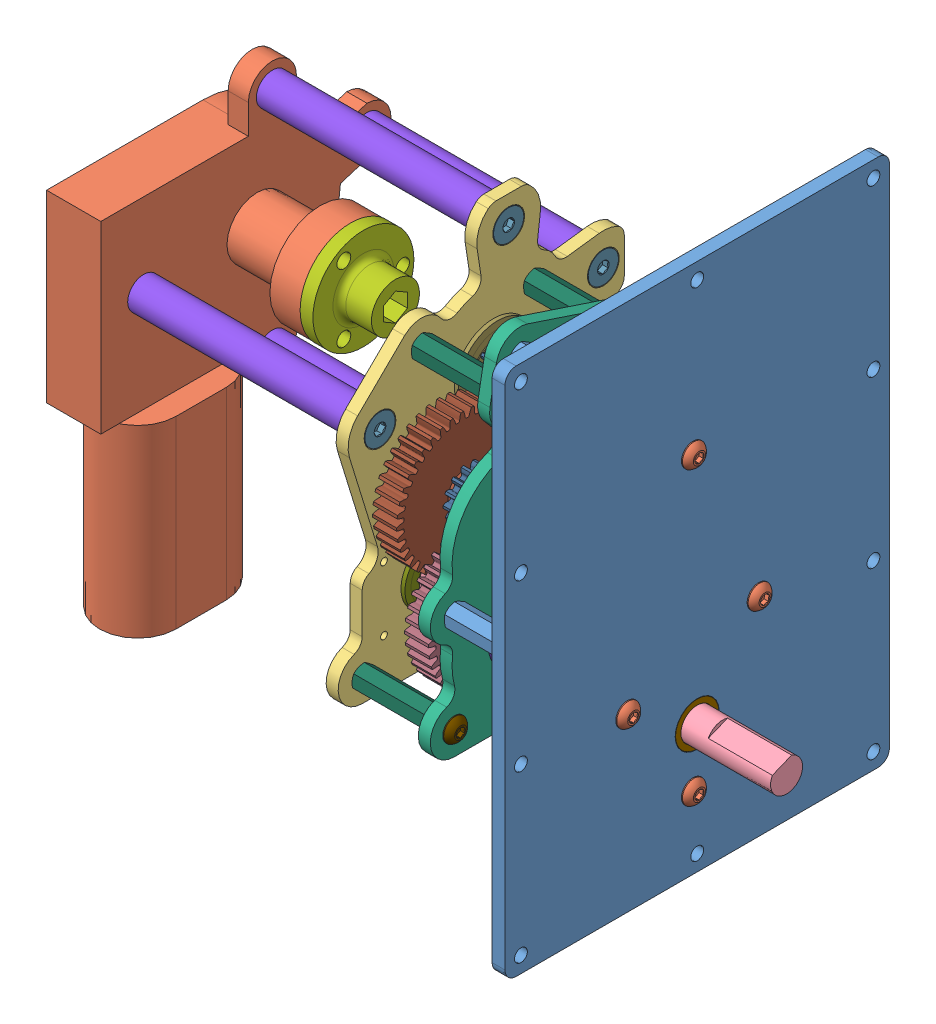
SolidWorks assembly Movable_Ballst_Motor_Assembly, configuration FEA. Lengths in mm.
Overall size (255.69 212.87 153.62).
50 component instances, 20 part files, 111 mates.
Components (placement in the parent):
- Ballast_Deck_Mount-1: Ballast_Deck_Mount [Default] at (82.4237 46.6127 298.7435) size (5.08 209.55 152.4)
- Ballast_Motor_Mock-1: Ballast_Motor_Mock [Default] at (-132.7513 189.2963 198.1531) x (1 0 0) z (0 -1 0) size (58.5 115.03 167.12)
- Ballast_Motor_Mount-1: Ballast_Motor_Mount [Default] at (-22.3513 65.6627 146.3435) x (1 0 0) z (0 -1 0) size (4.76 113.4 146.05)
- Movable_Ballast_Shaft-1: Movable_Ballast_Shaft [Default] at (122.9367 97.4127 222.5435) x (-1 0 0) z (0 -0.925827 -0.377948) size (146.05 14.66 12.7)
- Ballast_Gear_Shaft-1: Ballast_Gear_Shaft [Default] at (-23.9388 131.9059 222.5435) x (1 0 0) z (0 -0.052397 -0.998626) size (44.45 11 9.53)
- Ballast_GearBox_Mount-2: Ballast_GearBox_Mount [Default] at (14.1612 65.6627 165.3935) x (1 0 0) z (0 -1 0) size (4.76 87 134.58)
- Ballast_Motor_Hub-1: Ballast_Motor_Hub [Default] at (-74.2513 156.2963 198.1531) x (0 -1 0) z (1 0 0) size (40 40 17.78)
- CustomeStandoff_3_5in-1: CustomeStandoff_3_5in [92510A455] at (-66.8013 111.6963 192.1531) x (0 0 -1) z (1 0 0) size (12.7 12.7 88.9)
- CustomeStandoff_3_5in-2: CustomeStandoff_3_5in [92510A455] at (-66.8013 200.8963 192.1531) x (0 0 -1) z (1 0 0) size (12.7 12.7 88.9)
- CustomeStandoff_3_5in-3: CustomeStandoff_3_5in [92510A455] at (-66.8013 167.5963 154.6531) x (0 0.458553 0.888667) z (1 0 0) size (12.7 12.7 88.9)
- CustomeStandoff_3_5in-4: CustomeStandoff_3_5in [92510A455] at (-66.8013 156.2963 243.1531) x (0 0 -1) z (1 0 0) size (12.7 12.7 88.9)
- 13125K810_CHEMICAL-RESISTANT SHAFT SEAL-1: 13125K810_CHEMICAL-RESISTANT SHAFT SEAL [FEA] at (85.8146 97.4127 222.5435) size (3.38 17.46 17.46)
- 14tooth_VEX_217-2699.20121204-1: 14tooth_VEX_217-2699.20121204 [Default] at (-9.6767 156.2963 198.1531) x (0 -0.585847 -0.810422) z (1 0 0) size (20.3 20.6 12.65)
- 40tooth_VEX_217-2707.20121204-1: 40tooth_VEX_217-2707.20121204 [Default] at (-9.6767 131.9059 222.5435) x (0 0.052397 0.998626) z (-1 0 0) size (53.62 53.62 12.65)
- Hex_3_8in_Bearing_217-2735.20121205-5: Hex_3_8in_Bearing_217-2735.20121205 [Default] at (-23.9388 156.2963 198.1531) x (0 -0.131832 0.991272) z (0 0.991272 0.131832) size (31.12 7.94 31.12)
- 14tooth_VEX_217-2699.20121204-3: 14tooth_VEX_217-2699.20121204 [Default] at (2.9725 131.9059 222.5435) x (0 0.891034 0.453936) z (1 0 0) size (20.3 20.6 12.65)
- 40tooth_vex_1_2in)217-2708.20121204-1: 40tooth_vex_1_2in)217-2708.20121204 [Default] at (2.9725 97.4127 222.5435) x (0 0.925827 0.377948) z (-1 0 0) size (53.62 53.62 12.65)
- 92125A257_TYPE 18-8 SS FLAT-HEAD SOCKET CAP SCREW-1: 92125A257_TYPE 18-8 SS FLAT-HEAD SOCKET CAP SCREW [92125A257] at (-17.5888 111.6963 192.1531) x (0 -0.924225 -0.381849) z (1 0 0) size (12 12 101.09)
- 92125A257_TYPE 18-8 SS FLAT-HEAD SOCKET CAP SCREW-2: 92125A257_TYPE 18-8 SS FLAT-HEAD SOCKET CAP SCREW [92125A257] at (-17.5888 200.8963 192.1531) x (0 -0.446453 -0.894807) z (1 0 0) size (12 12 101.09)
- 92125A257_TYPE 18-8 SS FLAT-HEAD SOCKET CAP SCREW-3: 92125A257_TYPE 18-8 SS FLAT-HEAD SOCKET CAP SCREW [92125A257] at (-17.5888 156.2963 243.1531) x (0 -0.995417 0.095629) z (1 0 0) size (12 12 101.09)
- 92125A257_TYPE 18-8 SS FLAT-HEAD SOCKET CAP SCREW-4: 92125A257_TYPE 18-8 SS FLAT-HEAD SOCKET CAP SCREW [92125A257] at (-17.5888 167.5963 154.6531) x (0 -0.01521 -0.999884) z (1 0 0) size (12 12 101.09)
- 91780A253_ALUM FEM THRDED HEX STANDOFF-6: 91780A253_ALUM FEM THRDED HEX STANDOFF [FEA] at (-1.7138 75.1877 250.2231) x (0 0.803406 -0.595432) z (1 0 0) size (7.94 9.17 31.75)
- 91780A253_ALUM FEM THRDED HEX STANDOFF-5: 91780A253_ALUM FEM THRDED HEX STANDOFF [FEA] at (-1.7138 75.1877 198.1531) x (0 0.974 0.22655) z (-1 0 0) size (7.94 9.17 31.75)
- 91780A253_ALUM FEM THRDED HEX STANDOFF-3: 91780A253_ALUM FEM THRDED HEX STANDOFF [FEA] at (-1.7138 176.7877 226.7281) x (0 0 -1) z (1 0 0) size (7.94 9.17 31.75)
- 91780A253_ALUM FEM THRDED HEX STANDOFF-4: 91780A253_ALUM FEM THRDED HEX STANDOFF [FEA] at (-1.7138 176.7877 182.2781) x (0 -0.874202 0.485562) z (-1 0 0) size (7.94 9.17 31.75)
- 217-2733.20121205-1: 217-2733.20121205 [Default] at (12.5737 156.2963 198.1531) size (7.11 24.61 24.61)
- 217-2733.20121205-2: 217-2733.20121205 [Default] at (12.5737 131.9059 222.5435) size (7.11 24.61 24.61)
- 217-2733.20121205-3: 217-2733.20121205 [Default] at (-16.0013 131.9059 222.5435) x (-1 0 0) z (0 -0.924225 -0.381849) size (7.11 24.61 24.61)
- 217-2733.20121205-4: 217-2733.20121205 [Default] at (-16.0013 97.4127 222.5435) x (-1 0 0) z (0 -0.924225 -0.381849) size (7.11 24.61 24.61)
- Hex_1_2in_Bearing_217-3875-STEP-20140818-3: Hex_1_2in_Bearing_217-3875-STEP-20140818 [Default] at (20.5112 97.4127 222.5435) x (0 -0.990764 0.135601) z (0 -0.135601 -0.990764) size (31.12 7.94 31.12)
- 92949A269_18-8 SS BUTTON-HEAD SOCKET CAP SCREW-9: 92949A269_18-8 SS BUTTON-HEAD SOCKET CAP SCREW [FEA] at (-24.9167 75.1877 250.2231) x (0 0 1) z (-1 0 0) size (9.17 9.17 21.8)
- 92949A269_18-8 SS BUTTON-HEAD SOCKET CAP SCREW-10: 92949A269_18-8 SS BUTTON-HEAD SOCKET CAP SCREW [FEA] at (-24.9167 176.7877 226.7281) x (0 0.924225 0.381849) z (-1 0 0) size (9.17 9.17 21.8)
- 92949A269_18-8 SS BUTTON-HEAD SOCKET CAP SCREW-11: 92949A269_18-8 SS BUTTON-HEAD SOCKET CAP SCREW [FEA] at (-24.9167 176.7877 182.2781) x (0 0.924225 0.381849) z (-1 0 0) size (9.17 9.17 21.8)
- 92949A269_18-8 SS BUTTON-HEAD SOCKET CAP SCREW-12: 92949A269_18-8 SS BUTTON-HEAD SOCKET CAP SCREW [FEA] at (-24.9167 75.1877 198.1531) x (0 0 1) z (-1 0 0) size (9.17 9.17 21.8)
- 92949A269_18-8 SS BUTTON-HEAD SOCKET CAP SCREW-13: 92949A269_18-8 SS BUTTON-HEAD SOCKET CAP SCREW [FEA] at (21.4891 176.7877 182.2781) x (0 0 -1) z (1 0 0) size (9.17 9.17 21.8)
- 92949A269_18-8 SS BUTTON-HEAD SOCKET CAP SCREW-14: 92949A269_18-8 SS BUTTON-HEAD SOCKET CAP SCREW [FEA] at (21.4891 176.7877 226.7281) x (0 0 -1) z (1 0 0) size (9.17 9.17 21.8)
- 92949A269_18-8 SS BUTTON-HEAD SOCKET CAP SCREW-15: 92949A269_18-8 SS BUTTON-HEAD SOCKET CAP SCREW [FEA] at (21.4891 75.1877 198.1531) x (0 -0.924225 -0.381849) z (1 0 0) size (9.17 9.17 21.8)
- 92949A269_18-8 SS BUTTON-HEAD SOCKET CAP SCREW-16: 92949A269_18-8 SS BUTTON-HEAD SOCKET CAP SCREW [FEA] at (21.4891 75.1877 250.2231) x (0 0 -1) z (1 0 0) size (9.17 9.17 21.8)
- 91780A066_ALUM FEM THRDED HEX STANDOFF-1: 91780A066_ALUM FEM THRDED HEX STANDOFF [91780A066] at (50.6737 75.1877 224.1881) x (0 0 -1) z (1 0 0) size (7.94 9.17 63.5)
- 91780A066_ALUM FEM THRDED HEX STANDOFF-2: 91780A066_ALUM FEM THRDED HEX STANDOFF [91780A066] at (50.6737 114.6593 250.2231) x (0 0.893446 -0.44917) z (1 0 0) size (7.94 9.17 63.5)
- 91780A066_ALUM FEM THRDED HEX STANDOFF-3: 91780A066_ALUM FEM THRDED HEX STANDOFF [91780A066] at (50.6737 190.7197 224.1881) x (0 0 -1) z (1 0 0) size (7.94 9.17 63.5)
- 91780A066_ALUM FEM THRDED HEX STANDOFF-4: 91780A066_ALUM FEM THRDED HEX STANDOFF [91780A066] at (50.6737 129.1627 198.1531) x (0 0 -1) z (1 0 0) size (7.94 9.17 63.5)
- 92949A267_18-8 SS BUTTON-HEAD SOCKET CAP SCREW-1: 92949A267_18-8 SS BUTTON-HEAD SOCKET CAP SCREW [92949A267] at (90.0691 114.6593 250.2231) x (0 0 -1) z (1 0 0) size (9.17 9.17 18.62)
- 92949A267_18-8 SS BUTTON-HEAD SOCKET CAP SCREW-2: 92949A267_18-8 SS BUTTON-HEAD SOCKET CAP SCREW [92949A267] at (90.0691 75.1877 224.1881) x (0 0 -1) z (1 0 0) size (9.17 9.17 18.62)
- 92949A267_18-8 SS BUTTON-HEAD SOCKET CAP SCREW-3: 92949A267_18-8 SS BUTTON-HEAD SOCKET CAP SCREW [92949A267] at (90.0691 190.7197 224.1881) x (0 0 -1) z (1 0 0) size (9.17 9.17 18.62)
- 92949A267_18-8 SS BUTTON-HEAD SOCKET CAP SCREW-4: 92949A267_18-8 SS BUTTON-HEAD SOCKET CAP SCREW [92949A267] at (90.0691 129.1627 198.1531) x (0 0.96092 0.276827) z (1 0 0) size (9.17 9.17 18.62)
- 92949A267_18-8 SS BUTTON-HEAD SOCKET CAP SCREW-5: 92949A267_18-8 SS BUTTON-HEAD SOCKET CAP SCREW [92949A267] at (11.5958 114.6593 250.2231) x (0 0.111077 -0.993812) z (-1 0 0) size (9.17 9.17 18.62)
- 92949A267_18-8 SS BUTTON-HEAD SOCKET CAP SCREW-6: 92949A267_18-8 SS BUTTON-HEAD SOCKET CAP SCREW [92949A267] at (11.5958 190.7197 224.1881) x (0 0.111077 -0.993812) z (-1 0 0) size (9.17 9.17 18.62)
- 92949A267_18-8 SS BUTTON-HEAD SOCKET CAP SCREW-7: 92949A267_18-8 SS BUTTON-HEAD SOCKET CAP SCREW [92949A267] at (11.5958 75.1877 224.1881) x (0 0.111077 -0.993812) z (-1 0 0) size (9.17 9.17 18.62)
- 92949A267_18-8 SS BUTTON-HEAD SOCKET CAP SCREW-8: 92949A267_18-8 SS BUTTON-HEAD SOCKET CAP SCREW [92949A267] at (11.5958 129.1627 198.1531) x (0 0.111077 -0.993812) z (-1 0 0) size (9.17 9.17 18.62)
Mates (geometry in assembly coordinates):
- Concentric6: concentric anti-aligned: cylinder of Ballast_Motor_Mock-1 through (-74.2513 156.2963 198.1531) axis (-1 0 0) radius 20; cylinder of Ballast_Motor_Mount-1 through (-22.3513 156.2963 198.1531) axis (1 0 0) radius 14.2875
- Coincident62: coincident anti-aligned: plane of Ballast_Motor_Mock-1 through (-74.2513 156.2963 198.1531) normal (1 0 0); plane of Ballast_Motor_Hub-1 through (-74.2513 156.2963 198.1531) normal (-1 0 0)
- Concentric393: concentric aligned: cylinder of Ballast_Motor_Mock-1 through (-74.2513 156.2963 198.1531) axis (-1 0 0) radius 20; cylinder of Ballast_Motor_Hub-1 through (-69.1713 156.2963 198.1531) axis (-1 0 0) radius 20
- Concentric394: concentric aligned: cylinder of Ballast_Motor_Mock-1 through (-74.2513 142.8729 205.9031) axis (1 0 0) radius 2.1; cylinder of Ballast_Motor_Hub-1 through (-69.1713 142.8729 205.9031) axis (1 0 0) radius 2.75
- Concentric395: concentric anti-aligned: cylinder of Ballast_Motor_Mock-1 through (-111.2513 156.2963 243.1531) axis (1 0 0) radius 2.5; cylinder of CustomeStandoff_3_5in-4 through (-22.3513 156.2963 243.1531) axis (-1 0 0) radius 3.2004
- Coincident63: coincident anti-aligned: plane of Ballast_Motor_Mock-1 through (-111.2513 156.2963 198.1531) normal (1 0 0); plane of CustomeStandoff_3_5in-4 through (-111.2513 156.2963 243.1531) normal (-1 0 0)
- Parallel3: parallel anti-aligned: plane of Ballast_Motor_Mount-1 through (-22.3513 65.6627 146.3435) normal (-1 0 0); plane of CustomeStandoff_3_5in-4 through (-22.3513 156.2963 243.1531) normal (1 0 0)
- Concentric396: concentric anti-aligned: cylinder of Ballast_Motor_Mock-1 through (-111.2513 200.8963 192.1531) axis (1 0 0) radius 2.5; cylinder of CustomeStandoff_3_5in-2 through (-22.3513 200.8963 192.1531) axis (-1 0 0) radius 3.2004
- Coincident65: coincident anti-aligned: plane of Ballast_Motor_Mock-1 through (-111.2513 156.2963 198.1531) normal (1 0 0); plane of CustomeStandoff_3_5in-2 through (-111.2513 200.8963 192.1531) normal (-1 0 0)
- Concentric397: concentric anti-aligned: cylinder of Ballast_Motor_Mock-1 through (-111.2513 167.5963 154.6531) axis (1 0 0) radius 2.5; cylinder of CustomeStandoff_3_5in-3 through (-22.3513 167.5963 154.6531) axis (-1 0 0) radius 3.2004
- Coincident66: coincident anti-aligned: plane of Ballast_Motor_Mock-1 through (-111.2513 156.2963 198.1531) normal (1 0 0); plane of CustomeStandoff_3_5in-3 through (-111.2513 167.5963 154.6531) normal (-1 0 0)
- Concentric398: concentric anti-aligned: cylinder of Ballast_Motor_Mock-1 through (-111.2513 111.6963 192.1531) axis (1 0 0) radius 2.5; cylinder of CustomeStandoff_3_5in-1 through (-22.3513 111.6963 192.1531) axis (-1 0 0) radius 3.2004
- Coincident67: coincident anti-aligned: plane of Ballast_Motor_Mock-1 through (-111.2513 156.2963 198.1531) normal (1 0 0); plane of CustomeStandoff_3_5in-1 through (-111.2513 111.6963 192.1531) normal (-1 0 0)
- Concentric419: concentric aligned: cylinder of Movable_Ballast_Shaft-1 through (-23.1133 97.4127 222.5435) axis (1 0 0) radius 6.35; circle of 13125K810_CHEMICAL-RESISTANT SHAFT SEAL-1
- Coincident84: coincident aligned: plane of Ballast_Deck_Mount-1 through (87.5037 46.6127 298.7435) normal (1 0 0); plane of 13125K810_CHEMICAL-RESISTANT SHAFT SEAL-1 through (87.5037 105.9522 222.5435) normal (1 0 0)
- Concentric422: concentric aligned: cylinder of Ballast_Motor_Mount-1 through (-22.3513 156.2963 198.1531) axis (1 0 0) radius 14.2875; cylinder of Hex_3_8in_Bearing_217-2735.20121205-5 through (-23.9388 156.2963 198.1531) axis (1 0 0) radius 14.2748
- Coincident90: coincident anti-aligned: plane of Ballast_Motor_Mount-1 through (-17.5888 65.6627 146.3435) normal (1 0 0); plane of Hex_3_8in_Bearing_217-2735.20121205-5 through (-17.5888 154.2453 213.5748) normal (-1 0 0)
- Coincident98: coincident anti-aligned: plane of 14tooth_VEX_217-2699.20121204-1 through (-16.0013 156.2963 198.1531) normal (-1 0 0); plane of Hex_3_8in_Bearing_217-2735.20121205-5 through (-16.0013 155.4591 204.4477) normal (1 0 0)
- Coincident104: coincident anti-aligned: plane of 40tooth_VEX_217-2707.20121204-1 through (-3.3521 131.9059 222.5435) normal (1 0 0); plane of 14tooth_VEX_217-2699.20121204-3 through (-3.3521 131.9059 222.5435) normal (-1 0 0)
- Concentric425: concentric anti-aligned: cylinder of Movable_Ballast_Shaft-1 through (-23.1133 97.4127 222.5435) axis (1 0 0) radius 6.35; cylinder of Hex_1_2in_Bearing_217-3875-STEP-20140818-3 through (20.5112 97.4127 222.5435) axis (-1 0 0) radius 14.2748
- Coincident113: coincident aligned: plane of 14tooth_VEX_217-2699.20121204-3 through (9.2971 131.9059 222.5435) normal (1 0 0); plane of 40tooth_vex_1_2in)217-2708.20121204-1 through (9.2971 97.4127 222.5435) normal (1 0 0)
- Concentric432: concentric aligned: cylinder of Ballast_Motor_Mount-1 through (-17.5888 75.1877 198.1531) axis (1 0 0) radius 2.5527; cylinder of Ballast_GearBox_Mount-2 through (18.9237 75.1877 198.1531) axis (1 0 0) radius 2.5527
- Concentric433: concentric aligned: cylinder of Ballast_Motor_Mount-1 through (-17.5888 176.7877 226.7281) axis (1 0 0) radius 2.5527; cylinder of Ballast_GearBox_Mount-2 through (18.9237 176.7877 226.7281) axis (1 0 0) radius 2.5527
- Coincident134: coincident anti-aligned: plane of Ballast_Motor_Mount-1 through (-22.3513 65.6627 146.3435) normal (-1 0 0); plane of CustomeStandoff_3_5in-2 through (-22.3513 200.8963 192.1531) normal (1 0 0)
- Concentric437: concentric aligned: cylinder of Ballast_Motor_Mock-1 through (-111.2513 111.6963 192.1531) axis (1 0 0) radius 2.5; line of 92125A257_TYPE 18-8 SS FLAT-HEAD SOCKET CAP SCREW-1 through (-117.5888 111.6963 192.1531) axis (1 0 0)
- Coincident140: coincident aligned: cone of Ballast_Motor_Mount-1 through (-17.5888 111.6963 192.1531) axis (-1 0 0); cone of 92125A257_TYPE 18-8 SS FLAT-HEAD SOCKET CAP SCREW-1 through (-20.8888 111.6963 192.1531) axis (-1 0 0)
- Concentric438: concentric aligned: cylinder of Ballast_Motor_Mock-1 through (-111.2513 167.5963 154.6531) axis (1 0 0) radius 2.5; line of 92125A257_TYPE 18-8 SS FLAT-HEAD SOCKET CAP SCREW-4 through (-117.5888 167.5963 154.6531) axis (1 0 0)
- Coincident142: coincident aligned: cone of Ballast_Motor_Mount-1 through (-17.5888 167.5963 154.6531) axis (-1 0 0); cone of 92125A257_TYPE 18-8 SS FLAT-HEAD SOCKET CAP SCREW-4 through (-20.8888 167.5963 154.6531) axis (-1 0 0)
- Concentric439: concentric aligned: cylinder of Ballast_Motor_Mock-1 through (-111.2513 200.8963 192.1531) axis (1 0 0) radius 2.5; line of 92125A257_TYPE 18-8 SS FLAT-HEAD SOCKET CAP SCREW-2 through (-117.5888 200.8963 192.1531) axis (1 0 0)
- Coincident144: coincident aligned: cone of Ballast_Motor_Mount-1 through (-17.5888 200.8963 192.1531) axis (-1 0 0); cone of 92125A257_TYPE 18-8 SS FLAT-HEAD SOCKET CAP SCREW-2 through (-20.8888 200.8963 192.1531) axis (-1 0 0)
- Concentric440: concentric aligned: circle of Ballast_Motor_Mock-1; line of 92125A257_TYPE 18-8 SS FLAT-HEAD SOCKET CAP SCREW-3 through (-117.5888 156.2963 243.1531) axis (1 0 0)
- Coincident145: coincident aligned: cone of Ballast_Motor_Mount-1 through (-17.5888 156.2963 243.1531) axis (-1 0 0); cone of 92125A257_TYPE 18-8 SS FLAT-HEAD SOCKET CAP SCREW-3 through (-20.8888 156.2963 243.1531) axis (-1 0 0)
- Concentric446: concentric anti-aligned: circle of Ballast_Motor_Mount-1; circle of 91780A253_ALUM FEM THRDED HEX STANDOFF-6
- Coincident152: coincident anti-aligned: plane of Ballast_Motor_Mount-1 through (-17.5888 65.6627 146.3435) normal (1 0 0); plane of 91780A253_ALUM FEM THRDED HEX STANDOFF-6 through (-17.5888 77.9164 253.9049) normal (-1 0 0)
- Coincident153: coincident anti-aligned: circle of Ballast_GearBox_Mount-2; plane of 91780A253_ALUM FEM THRDED HEX STANDOFF-6 through (14.1612 77.9164 253.9049) normal (1 0 0)
- Concentric447: concentric aligned: cylinder of Ballast_Motor_Mount-1 through (-17.5888 75.1877 198.1531) axis (1 0 0) radius 2.5527; circle of 91780A253_ALUM FEM THRDED HEX STANDOFF-5
- Coincident154: coincident anti-aligned: plane of Ballast_Motor_Mount-1 through (-17.5888 65.6627 146.3435) normal (1 0 0); plane of 91780A253_ALUM FEM THRDED HEX STANDOFF-5 through (-17.5888 76.2259 193.6895) normal (-1 0 0)
- Concentric448: concentric aligned: cylinder of Ballast_Motor_Mount-1 through (-17.5888 176.7877 182.2781) axis (1 0 0) radius 2.5527; circle of 91780A253_ALUM FEM THRDED HEX STANDOFF-4
- Coincident155: coincident anti-aligned: plane of Ballast_Motor_Mount-1 through (-17.5888 65.6627 146.3435) normal (1 0 0); plane of 91780A253_ALUM FEM THRDED HEX STANDOFF-4 through (-17.5888 179.0129 186.2843) normal (-1 0 0)
- Parallel5: parallel aligned: plane of Ballast_Deck_Mount-1 through (87.5037 46.6127 146.3435) normal (0 0 -1); plane of Ballast_Motor_Mount-1 through (-17.5888 65.6627 146.3435) normal (0 0 -1)
- Concentric449: concentric anti-aligned: cylinder of Ballast_Motor_Mount-1 through (-17.5888 176.7877 226.7281) axis (1 0 0) radius 2.5527; circle of 91780A253_ALUM FEM THRDED HEX STANDOFF-3
- Coincident156: coincident anti-aligned: plane of Ballast_Motor_Mount-1 through (-17.5888 65.6627 146.3435) normal (1 0 0); plane of 91780A253_ALUM FEM THRDED HEX STANDOFF-3 through (-17.5888 181.3704 226.7281) normal (-1 0 0)
- Concentric450: concentric aligned: cylinder of Ballast_GearBox_Mount-2 through (-26.25 156.2963 198.1531) axis (1 0 0) radius 11.1125; circle of 217-2733.20121205-1
- Coincident159: coincident anti-aligned: plane of Ballast_GearBox_Mount-2 through (14.1612 65.6627 165.3935) normal (-1 0 0); plane of 217-2733.20121205-1 through (14.1612 167.4088 198.1531) normal (1 0 0)
- Coincident160: coincident anti-aligned: plane of Ballast_GearBox_Mount-2 through (14.1612 65.6627 165.3935) normal (-1 0 0); plane of 217-2733.20121205-2 through (14.1612 143.0184 222.5435) normal (1 0 0)
- Concentric451: concentric anti-aligned: cylinder of Ballast_GearBox_Mount-2 through (14.1612 131.9059 222.5435) axis (1 0 0) radius 11.1125; cylinder of 217-2733.20121205-2 through (12.5737 131.9059 222.5435) axis (-1 0 0) radius 11.1125
- Coincident161: coincident anti-aligned: plane of Ballast_Motor_Mount-1 through (-17.5888 65.6627 146.3435) normal (1 0 0); plane of 217-2733.20121205-3 through (-17.5888 136.1492 212.273) normal (-1 0 0)
- Concentric452: concentric aligned: cylinder of Ballast_Motor_Mount-1 through (-22.3513 131.9059 222.5435) axis (1 0 0) radius 11.1125; cylinder of 217-2733.20121205-3 through (-16.0013 131.9059 222.5435) axis (1 0 0) radius 12.3063
- Coincident162: coincident anti-aligned: plane of Ballast_Motor_Mount-1 through (-17.5888 65.6627 146.3435) normal (1 0 0); plane of 217-2733.20121205-4 through (-17.5888 101.656 212.273) normal (-1 0 0)
- Concentric453: concentric aligned: cylinder of Ballast_Motor_Mount-1 through (-22.3513 97.4127 222.5435) axis (1 0 0) radius 11.1125; cylinder of 217-2733.20121205-4 through (-16.0013 97.4127 222.5435) axis (1 0 0) radius 11.1125
- Coincident163: coincident anti-aligned: plane of Ballast_GearBox_Mount-2 through (14.1612 65.6627 165.3935) normal (-1 0 0); plane of Hex_1_2in_Bearing_217-3875-STEP-20140818-3 through (14.1612 81.9989 224.6531) normal (1 0 0)
- Concentric455: concentric anti-aligned: cylinder of Ballast_GearBox_Mount-2 through (14.1612 97.4127 222.5435) axis (1 0 0) radius 14.2875; cylinder of Hex_1_2in_Bearing_217-3875-STEP-20140818-3 through (20.5112 97.4127 222.5435) axis (-1 0 0) radius 14.2748
- Parallel7: parallel anti-aligned: plane of Movable_Ballast_Shaft-1 through (84.0112 90.1481 223.5377) normal (0 -0.790226 0.612816); plane of Hex_1_2in_Bearing_217-3875-STEP-20140818-3 through (20.5112 90.1366 223.5393) normal (0 0.790226 -0.612816)
- Coincident165: coincident anti-aligned: plane of Movable_Ballast_Shaft-1 through (-16.0013 97.4127 222.5435) normal (-1 0 0); plane of 217-2733.20121205-4 through (-16.0013 99.8374 216.6746) normal (1 0 0)
- Coincident174: coincident anti-aligned: plane of Ballast_GearBox_Mount-2 through (18.9237 65.6627 165.3935) normal (1 0 0); plane of 92949A269_18-8 SS BUTTON-HEAD SOCKET CAP SCREW-13 through (18.9237 172.203 182.2781) normal (-1 0 0)
- Concentric464: concentric aligned: cylinder of Ballast_GearBox_Mount-2 through (18.9237 176.7877 182.2781) axis (1 0 0) radius 2.5527; circle of 92949A269_18-8 SS BUTTON-HEAD SOCKET CAP SCREW-13
- Coincident175: coincident anti-aligned: plane of Ballast_GearBox_Mount-2 through (18.9237 65.6627 165.3935) normal (1 0 0); plane of 92949A269_18-8 SS BUTTON-HEAD SOCKET CAP SCREW-14 through (18.9237 172.203 226.7281) normal (-1 0 0)
- Concentric465: concentric aligned: cylinder of Ballast_GearBox_Mount-2 through (18.9237 176.7877 226.7281) axis (1 0 0) radius 2.5527; circle of 92949A269_18-8 SS BUTTON-HEAD SOCKET CAP SCREW-14
- Coincident176: coincident aligned: plane of Ballast_GearBox_Mount-2 through (18.9237 65.6627 165.3935) normal (1 0 0); circle of 92949A269_18-8 SS BUTTON-HEAD SOCKET CAP SCREW-15
- Concentric467: concentric aligned: cylinder of Ballast_GearBox_Mount-2 through (18.9237 75.1877 198.1531) axis (1 0 0) radius 2.5527; circle of 92949A269_18-8 SS BUTTON-HEAD SOCKET CAP SCREW-15
- Coincident177: coincident anti-aligned: plane of Ballast_GearBox_Mount-2 through (18.9237 65.6627 165.3935) normal (1 0 0); plane of 92949A269_18-8 SS BUTTON-HEAD SOCKET CAP SCREW-16 through (18.9237 70.603 250.2231) normal (-1 0 0)
- Concentric468: concentric aligned: circle of Ballast_GearBox_Mount-2; circle of 92949A269_18-8 SS BUTTON-HEAD SOCKET CAP SCREW-16
- Coincident178: coincident anti-aligned: plane of Ballast_Motor_Mount-1 through (-22.3513 65.6627 146.3435) normal (-1 0 0); plane of 92949A269_18-8 SS BUTTON-HEAD SOCKET CAP SCREW-9 through (-22.3513 70.603 250.2231) normal (1 0 0)
- Concentric469: concentric anti-aligned: circle of Ballast_Motor_Mount-1; circle of 92949A269_18-8 SS BUTTON-HEAD SOCKET CAP SCREW-9
- Coincident179: coincident anti-aligned: plane of Ballast_Motor_Mount-1 through (-22.3513 65.6627 146.3435) normal (-1 0 0); plane of 92949A269_18-8 SS BUTTON-HEAD SOCKET CAP SCREW-12 through (-22.3513 70.603 198.1531) normal (1 0 0)
- Concentric470: concentric anti-aligned: cylinder of Ballast_Motor_Mount-1 through (-17.5888 75.1877 198.1531) axis (1 0 0) radius 2.5527; circle of 92949A269_18-8 SS BUTTON-HEAD SOCKET CAP SCREW-12
- Coincident180: coincident aligned: plane of Ballast_Motor_Mount-1 through (-22.3513 65.6627 146.3435) normal (-1 0 0); circle of 92949A269_18-8 SS BUTTON-HEAD SOCKET CAP SCREW-11
- Concentric471: concentric anti-aligned: cylinder of Ballast_Motor_Mount-1 through (-17.5888 176.7877 182.2781) axis (1 0 0) radius 2.5527; circle of 92949A269_18-8 SS BUTTON-HEAD SOCKET CAP SCREW-11
- Coincident181: coincident aligned: plane of Ballast_Motor_Mount-1 through (-22.3513 65.6627 146.3435) normal (-1 0 0); circle of 92949A269_18-8 SS BUTTON-HEAD SOCKET CAP SCREW-10
- Concentric472: concentric anti-aligned: cylinder of Ballast_Motor_Mount-1 through (-17.5888 176.7877 226.7281) axis (1 0 0) radius 2.5527; circle of 92949A269_18-8 SS BUTTON-HEAD SOCKET CAP SCREW-10
- Concentric473: concentric anti-aligned: cylinder of Ballast_Gear_Shaft-1 through (-16.0013 131.9059 222.5435) axis (-1 0 0) radius 4.7625; cylinder of 217-2733.20121205-3 through (-16.0013 131.9059 222.5435) axis (1 0 0) radius 4.7625
- Coincident182: coincident anti-aligned: plane of Ballast_Gear_Shaft-1 through (12.5737 131.9059 222.5435) normal (1 0 0); plane of 217-2733.20121205-2 through (12.5737 138.2559 222.5435) normal (-1 0 0)
- GearMate1: gear = 355.6 : 1016 mm: circle of 40tooth_VEX_217-2707.20121204-1; circle of 14tooth_VEX_217-2699.20121204-1
- GearMate2: gear = 355.6 : 1016 mm: circle of 40tooth_vex_1_2in)217-2708.20121204-1; circle of 14tooth_VEX_217-2699.20121204-3
- Parallel10: parallel aligned: plane of Movable_Ballast_Shaft-1 through (84.0112 90.1481 223.5377) normal (0 -0.790226 0.612816); plane of 40tooth_vex_1_2in)217-2708.20121204-1 through (-3.3521 100.2006 215.7142) normal (0 -0.790226 0.612816)
- Concentric476: concentric anti-aligned: cylinder of 40tooth_VEX_217-2707.20121204-1 through (-16.0013 131.9059 222.5435) axis (1 0 0) radius 6.35; cylinder of 14tooth_VEX_217-2699.20121204-3 through (9.2971 131.9059 222.5435) axis (-1 0 0) radius 6.35
- Parallel14: parallel: plane of Ballast_Gear_Shaft-1 through (20.5112 137.3976 222.2553) normal (0 0.891034 0.453936); line of 14tooth_VEX_217-2699.20121204-3 through (9.2971 134.9253 227.1922) axis (0 0.453936 -0.891034)
- Coincident193: coincident anti-aligned: plane of Ballast_Gear_Shaft-1 through (-16.0013 131.9059 222.5435) normal (-1 0 0); plane of 217-2733.20121205-3 through (-16.0013 134.3306 216.6746) normal (1 0 0)
- Coincident195: coincident anti-aligned: plane of 40tooth_VEX_217-2707.20121204-1 through (-16.0013 131.9059 222.5435) normal (-1 0 0); plane of 217-2733.20121205-3 through (-16.0013 134.3306 216.6746) normal (1 0 0)
- Concentric478: concentric anti-aligned: cylinder of Ballast_Gear_Shaft-1 through (12.5737 131.9059 222.5435) axis (1 0 0) radius 4.7625; cylinder of 14tooth_VEX_217-2699.20121204-3 through (9.2971 131.9059 222.5435) axis (-1 0 0) radius 6.35
- Parallel16: parallel aligned: plane of Ballast_Gear_Shaft-1 through (20.5112 137.3976 222.2553) normal (0 0.891034 0.453936); plane of 14tooth_VEX_217-2699.20121204-3 through (-3.3521 126.3703 222.8339) normal (0 0.891034 0.453936)
- Parallel17: parallel anti-aligned: plane of Ballast_Gear_Shaft-1 through (20.5112 126.4142 222.8316) normal (0 -0.891034 -0.453936); plane of 40tooth_VEX_217-2707.20121204-1 through (-16.0013 126.3703 222.8339) normal (0 0.891034 0.453936)
- Concentric479: concentric aligned: cylinder of Movable_Ballast_Shaft-1 through (-23.1133 97.4127 222.5435) axis (1 0 0) radius 6.35; cylinder of 40tooth_vex_1_2in)217-2708.20121204-1 through (-3.3521 97.4127 222.5435) axis (1 0 0) radius 8.89
- Concentric480: concentric aligned: cylinder of Ballast_Deck_Mount-1 through (82.4237 97.4127 222.5435) axis (1 0 0) radius 8.7312; cylinder of 13125K810_CHEMICAL-RESISTANT SHAFT SEAL-1 through (84.1255 97.4127 222.5435) axis (1 0 0) radius 8.7312
- Coincident196: coincident anti-aligned: plane of Ballast_GearBox_Mount-2 through (18.9237 65.6627 165.3935) normal (1 0 0); plane of 91780A066_ALUM FEM THRDED HEX STANDOFF-1 through (18.9237 79.7704 224.1881) normal (-1 0 0)
- Coincident197: coincident anti-aligned: plane of Ballast_Deck_Mount-1 through (82.4237 46.6127 298.7435) normal (-1 0 0); plane of 91780A066_ALUM FEM THRDED HEX STANDOFF-1 through (82.4237 79.7704 224.1881) normal (1 0 0)
- Concentric481: concentric aligned: cylinder of Ballast_GearBox_Mount-2 through (18.9237 75.1877 224.1881) axis (1 0 0) radius 2.8067; cone of 91780A066_ALUM FEM THRDED HEX STANDOFF-1 through (18.9237 75.1877 224.1881) axis (1 0 0)
- Coincident199: coincident anti-aligned: plane of Ballast_GearBox_Mount-2 through (18.9237 65.6627 165.3935) normal (1 0 0); plane of 91780A066_ALUM FEM THRDED HEX STANDOFF-4 through (18.9237 133.7454 198.1531) normal (-1 0 0)
- Coincident200: coincident anti-aligned: plane of Ballast_GearBox_Mount-2 through (18.9237 65.6627 165.3935) normal (1 0 0); plane of 91780A066_ALUM FEM THRDED HEX STANDOFF-3 through (18.9237 195.3024 224.1881) normal (-1 0 0)
- Concentric483: concentric anti-aligned: cylinder of Ballast_GearBox_Mount-2 through (18.9237 190.7197 224.1881) axis (1 0 0) radius 2.8067; circle of 91780A066_ALUM FEM THRDED HEX STANDOFF-3
- Concentric484: concentric anti-aligned: cylinder of Ballast_GearBox_Mount-2 through (18.9237 114.6593 250.2231) axis (1 0 0) radius 2.8067; circle of 91780A066_ALUM FEM THRDED HEX STANDOFF-2
- Coincident201: coincident anti-aligned: plane of Ballast_GearBox_Mount-2 through (18.9237 65.6627 165.3935) normal (1 0 0); plane of 91780A066_ALUM FEM THRDED HEX STANDOFF-2 through (18.9237 116.7177 254.3175) normal (-1 0 0)
- Concentric485: concentric anti-aligned: circle of 14tooth_VEX_217-2699.20121204-1; cylinder of Hex_3_8in_Bearing_217-2735.20121205-5 through (-23.9388 156.2963 198.1531) axis (1 0 0) radius 9.525
- Concentric494: concentric anti-aligned: cylinder of Ballast_GearBox_Mount-2 through (18.9237 129.1627 198.1531) axis (1 0 0) radius 2.8067; cylinder of 91780A066_ALUM FEM THRDED HEX STANDOFF-4 through (82.4237 129.1627 198.1531) axis (-1 0 0) radius 2.413
- Concentric495: concentric anti-aligned: cylinder of Ballast_Deck_Mount-1 through (87.5037 114.6593 250.2231) axis (1 0 0) radius 2.5527; cylinder of 92949A267_18-8 SS BUTTON-HEAD SOCKET CAP SCREW-1 through (71.6287 114.6593 250.2231) axis (-1 0 0) radius 2.413
- Coincident209: coincident anti-aligned: plane of Ballast_Deck_Mount-1 through (87.5037 46.6127 298.7435) normal (1 0 0); plane of 92949A267_18-8 SS BUTTON-HEAD SOCKET CAP SCREW-1 through (87.5037 110.0746 250.2231) normal (-1 0 0)
- Concentric496: concentric anti-aligned: cylinder of Ballast_Deck_Mount-1 through (87.5037 75.1877 224.1881) axis (1 0 0) radius 2.5527; cylinder of 92949A267_18-8 SS BUTTON-HEAD SOCKET CAP SCREW-2 through (71.6287 75.1877 224.1881) axis (-1 0 0) radius 2.413
- Coincident210: coincident anti-aligned: plane of Ballast_Deck_Mount-1 through (87.5037 46.6127 298.7435) normal (1 0 0); plane of 92949A267_18-8 SS BUTTON-HEAD SOCKET CAP SCREW-2 through (87.5037 70.603 224.1881) normal (-1 0 0)
- Concentric497: concentric anti-aligned: cylinder of Ballast_Deck_Mount-1 through (87.5037 129.1627 198.1531) axis (1 0 0) radius 2.5527; cylinder of 92949A267_18-8 SS BUTTON-HEAD SOCKET CAP SCREW-4 through (71.6287 129.1627 198.1531) axis (-1 0 0) radius 2.413
- Coincident211: coincident anti-aligned: plane of Ballast_Deck_Mount-1 through (87.5037 46.6127 298.7435) normal (1 0 0); plane of 92949A267_18-8 SS BUTTON-HEAD SOCKET CAP SCREW-4 through (87.5037 130.4319 193.7475) normal (-1 0 0)
- Concentric498: concentric anti-aligned: cylinder of Ballast_Deck_Mount-1 through (87.5037 190.7197 224.1881) axis (1 0 0) radius 2.5527; cylinder of 92949A267_18-8 SS BUTTON-HEAD SOCKET CAP SCREW-3 through (71.6287 190.7197 224.1881) axis (-1 0 0) radius 2.413
- Coincident212: coincident anti-aligned: plane of Ballast_Deck_Mount-1 through (87.5037 46.6127 298.7435) normal (1 0 0); plane of 92949A267_18-8 SS BUTTON-HEAD SOCKET CAP SCREW-3 through (87.5037 186.135 224.1881) normal (-1 0 0)
- Concentric499: concentric aligned: cylinder of Ballast_GearBox_Mount-2 through (18.9237 75.1877 224.1881) axis (1 0 0) radius 2.8067; cylinder of 92949A267_18-8 SS BUTTON-HEAD SOCKET CAP SCREW-7 through (30.0362 75.1877 224.1881) axis (1 0 0) radius 2.413
- Coincident213: coincident anti-aligned: plane of Ballast_GearBox_Mount-2 through (14.1612 65.6627 165.3935) normal (-1 0 0); plane of 92949A267_18-8 SS BUTTON-HEAD SOCKET CAP SCREW-7 through (14.1612 79.744 224.6973) normal (1 0 0)
- Concentric500: concentric aligned: cylinder of Ballast_GearBox_Mount-2 through (18.9237 129.1627 198.1531) axis (1 0 0) radius 2.8067; cylinder of 92949A267_18-8 SS BUTTON-HEAD SOCKET CAP SCREW-8 through (30.0362 129.1627 198.1531) axis (1 0 0) radius 2.413
- Coincident214: coincident anti-aligned: plane of Ballast_GearBox_Mount-2 through (14.1612 65.6627 165.3935) normal (-1 0 0); plane of 92949A267_18-8 SS BUTTON-HEAD SOCKET CAP SCREW-8 through (14.1612 133.719 198.6623) normal (1 0 0)
- Concentric501: concentric aligned: cylinder of Ballast_GearBox_Mount-2 through (18.9237 190.7197 224.1881) axis (1 0 0) radius 2.8067; cylinder of 92949A267_18-8 SS BUTTON-HEAD SOCKET CAP SCREW-6 through (30.0362 190.7197 224.1881) axis (1 0 0) radius 2.413
- Coincident215: coincident anti-aligned: plane of Ballast_GearBox_Mount-2 through (14.1612 65.6627 165.3935) normal (-1 0 0); plane of 92949A267_18-8 SS BUTTON-HEAD SOCKET CAP SCREW-6 through (14.1612 195.276 224.6973) normal (1 0 0)
- Concentric502: concentric aligned: cylinder of Ballast_GearBox_Mount-2 through (18.9237 114.6593 250.2231) axis (1 0 0) radius 2.8067; cylinder of 92949A267_18-8 SS BUTTON-HEAD SOCKET CAP SCREW-5 through (30.0362 114.6593 250.2231) axis (1 0 0) radius 2.413
- Coincident216: coincident anti-aligned: plane of Ballast_GearBox_Mount-2 through (14.1612 65.6627 165.3935) normal (-1 0 0); plane of 92949A267_18-8 SS BUTTON-HEAD SOCKET CAP SCREW-5 through (14.1612 119.2156 250.7323) normal (1 0 0)
- Parallel18: parallel aligned: plane of Ballast_Motor_Mock-1 through (-117.6013 43.2963 239.1531) normal (0 -1 0); plane of Ballast_GearBox_Mount-2 through (18.9237 65.6627 165.3935) normal (0 -1 0)
